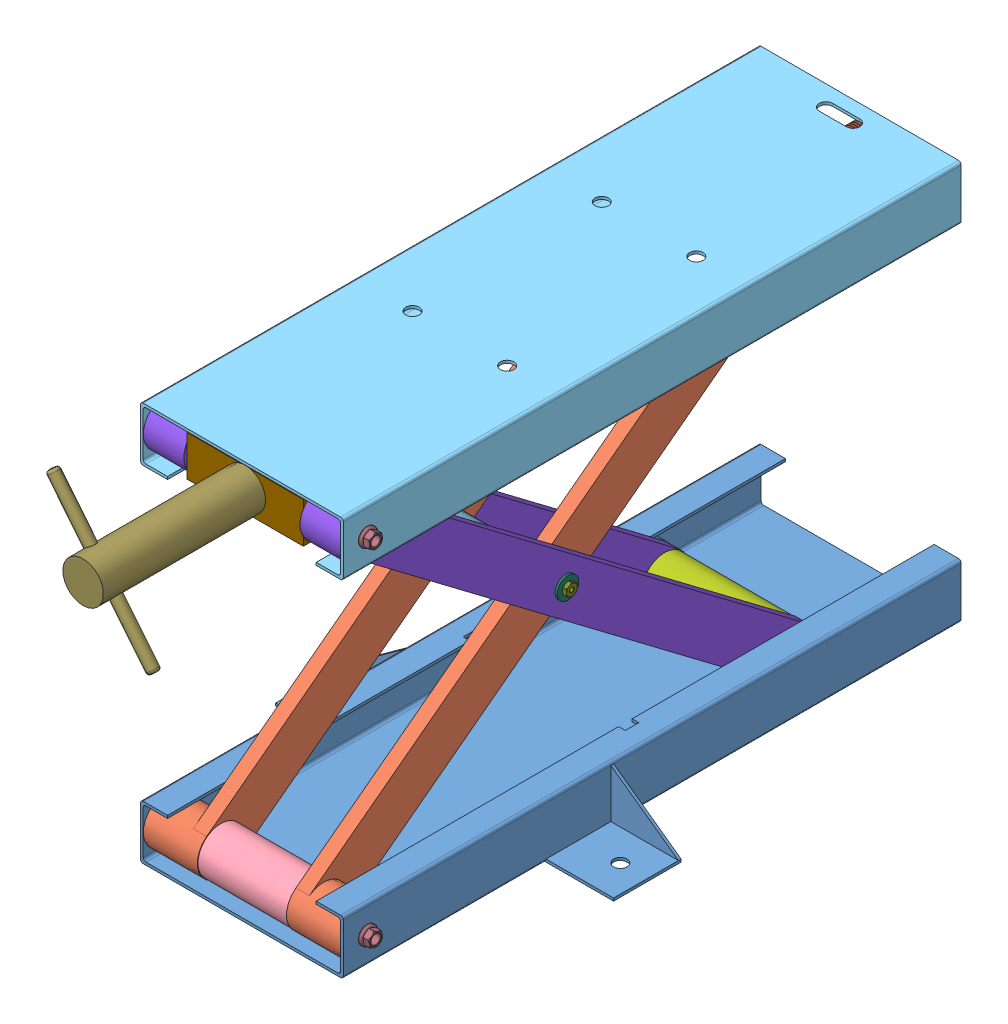
SolidWorks assembly Ensamblaje1, configuration Predeterminado. Lengths in mm.
Overall size (250 336.92 576.75).
25 component instances, 16 part files, 58 mates.
Components (placement in the parent):
- Base-1: Base [Predeterminado] at (-9.1737 1.9112 457.2) size (250 40 457.2)
- Pieza2-1: Pieza2 [Predeterminado] at (23.8263 129.7204 499.1586) x (0 0.602874 -0.797837) z (1 0 0) size (459 35 40)
- Pieza2-2: Pieza2 [Predeterminado] at (-42.1737 129.7204 499.1586) x (0 0.602874 -0.797837) z (-1 0 0) size (459 35 40)
- rueda-1: rueda [Predeterminado] at (-67.1737 257.5296 330.0173) x (0 -0.999437 -0.033543) z (1 0 0) size (35 35 30)
- rueda-2: rueda [Predeterminado] at (48.8263 257.5296 330.0173) x (0 0.027359 0.999626) z (-1 0 0) size (35 35 30)
- Pieza4-1: Pieza4 [Predeterminado] at (-9.1737 1.9112 668.3) x (0 0 -1) z (1 0 0) size (34 34 66)
- Base2-1: Base2 [Predeterminado] at (-9.1737 257.0296 457.2) x (-1 0 0) z (0 0 1) size (150 40 457.2)
- rueda2-1: rueda2 [Predeterminado] at (53.8263 1.4112 330.0173) x (0 0.027839 0.999612) z (-1 0 0) size (35 35 20)
- rueda2-2: rueda2 [Predeterminado] at (-72.1737 1.4112 330.0173) x (0 0.704882 0.709324) z (-1 0 0) size (35 35 20)
- Pieza5-1: Pieza5 [Predeterminado] at (-9.1737 1.4112 330.0173) x (0 -0.989655 -0.143469) z (-1 0 0) size (34 34 86)
- Pieza3-3: Pieza3 [Predeterminado] at (-52.1737 129.2204 499.1586) x (0 -0.602874 -0.797837) z (-1 0 0) size (459 35 30)
- Pieza3-4: Pieza3 [Predeterminado] at (33.8263 129.2204 499.1586) x (0 -0.602874 -0.797837) z (1 0 0) size (459 35 30)
- Pieza6-1: Pieza6 [Predeterminado] at (-9.1737 257.0296 668.3) size (86 30 30)
- Pieza7-1: Pieza7 [Predeterminado] at (-9.1737 257.5296 330.0173) size (66 30 30)
- rosca-1: rosca [Predeterminado] at (-9.1737 257.5296 683.3) x (-0.145567 0.989348 0) z (0 0 1) size (23.09 20.1 506.75)
- Pieza8-1: Pieza8 [Predeterminado] at (-9.1737 257.5296 683.3) x (0.776829 0.629712 0) z (0 0 1) size (30 120 120)
- hex nuts_21042_mil-4: hex nuts_21042_mil [NUT 21042 0.3125-24-N] at (72.5827 257.0296 668.3) x (0 0 -1) z (1 0 0) size (13.21 13.21 6.76)
- hex nuts_21042_mil-5: hex nuts_21042_mil [NUT 21042 0.3125-24-N] at (-90.9301 1.9112 668.3) x (0 -0.531517 0.847048) z (-1 0 0) size (13.21 13.21 6.76)
- hex nuts_21042_mil-6: hex nuts_21042_mil [NUT 21042 0.3125-24-N] at (72.5827 1.9112 668.3) x (0 -0.763369 -0.645962) z (1 0 0) size (13.21 13.21 6.76)
- hex nuts_21042_mil-7: hex nuts_21042_mil [NUT 21042 0.3125-24-N] at (-90.9301 257.0296 668.3) x (0 -0.851871 -0.523752) z (-1 0 0) size (13.21 13.21 6.76)
- Pieza9-1: Pieza9 [Predeterminado] at (-9.1737 129.2204 499.1586) x (0 0 1) z (-1 0 0) size (15 15 106)
- flat_mil-3: flat_mil [FLAT 0.281-0.625] at (43.8263 129.2204 499.1586) x (-1 0 0) z (0 0.924225 0.381849) size (1.65 15.88 15.88)
- flat_mil-4: flat_mil [FLAT 0.281-0.625] at (-62.1737 129.2204 499.1586) size (1.65 15.88 15.88)
- hex nuts_35650_mil-2: hex nuts_35650_mil [NUT 35650 0.138-40-N] at (48.3729 129.2204 499.1586) x (0 0 -1) z (1 0 0) size (8 9.24 2.9)
- hex nuts_35650_mil-3: hex nuts_35650_mil [NUT 35650 0.138-40-N] at (-66.7203 129.2204 499.1586) x (0 0 1) z (-1 0 0) size (8 9.24 2.9)
Mates (geometry in assembly coordinates):
- Concéntrica1: concentric anti-aligned: cylinder of Base-1 through (-84.1737 1.9112 668.3) axis (1 0 0) radius 5; cylinder of Pieza2-1 through (33.8263 1.9112 668.3) axis (-1 0 0) radius 5
- Coincidente1: coincident anti-aligned: plane of Base-1 through (63.8263 -16.0888 685.8) normal (-1 0 0); plane of Pieza2-1 through (63.8263 1.9112 668.3) normal (1 0 0)
- Coincidente2: coincident anti-aligned: plane of Base-1 through (-82.1737 -16.0888 685.8) normal (1 0 0); plane of Pieza2-2 through (-82.1737 1.9112 668.3) normal (-1 0 0)
- Concéntrica2: concentric aligned: cylinder of Base-1 through (-84.1737 1.9112 668.3) axis (1 0 0) radius 5; cylinder of Pieza2-2 through (-52.1737 1.9112 668.3) axis (1 0 0) radius 5
- Concéntrica3: concentric anti-aligned: cylinder of Pieza2-1 through (33.8263 257.5296 330.0173) axis (-1 0 0) radius 5; cylinder of rueda-2 through (33.8263 257.5296 330.0173) axis (1 0 0) radius 5
- Coincidente3: coincident anti-aligned: plane of Pieza2-1 through (33.8263 1.9112 668.3) normal (1 0 0); plane of rueda-2 through (33.8263 257.5296 330.0173) normal (-1 0 0)
- Concéntrica4: concentric anti-aligned: cylinder of Pieza2-2 through (-52.1737 257.5296 330.0173) axis (1 0 0) radius 5; cylinder of rueda-1 through (-52.1737 257.5296 330.0173) axis (-1 0 0) radius 5
- Coincidente4: coincident anti-aligned: plane of Pieza2-2 through (-52.1737 1.9112 668.3) normal (-1 0 0); plane of rueda-1 through (-52.1737 257.5296 330.0173) normal (1 0 0)
- Concéntrica5: concentric anti-aligned: cylinder of Pieza2-2 through (-52.1737 1.9112 668.3) axis (1 0 0) radius 5; cylinder of Pieza4-1 through (23.8263 1.9112 668.3) axis (-1 0 0) radius 5
- Coincidente5: coincident anti-aligned: plane of Pieza2-1 through (23.8263 1.9112 668.3) normal (-1 0 0); plane of Pieza4-1 through (23.8263 1.9112 668.3) normal (1 0 0)
- Tangente1: tangent anti-aligned: cylinder of rueda-2 through (33.8263 257.5296 330.0173) axis (1 0 0) radius 17.5; plane of Base2-1 through (63.8263 275.0296 685.8) normal (0 -1 0)
- Coincidente9: coincident aligned: plane of Base-1 through (65.8263 -18.0888 685.8) normal (1 0 0); plane of Base2-1 through (65.8263 277.0296 685.8) normal (1 0 0)
- Paralelo3: parallel aligned: plane of Base-1 through (-82.1737 -16.0888 685.8) normal (0 1 0); plane of Base2-1 through (65.8263 277.0296 685.8) normal (0 1 0)
- Tangente2: tangent anti-aligned: cylinder of rueda-1 through (-52.1737 257.5296 330.0173) axis (-1 0 0) radius 17.5; plane of Base2-1 through (63.8263 275.0296 685.8) normal (0 -1 0)
- Coincidente11: coincident aligned: plane of Base-1 through (-9.1737 1.9112 228.6) normal (0 0 -1); plane of Base2-1 through (-9.1737 257.0296 228.6) normal (0 0 -1)
- Distancia límite1: limit distance = 215.1184 mm anti-aligned: plane of Base-1 through (-84.1737 21.9112 685.8) normal (0 1 0); plane of Base2-1 through (-84.1737 237.0296 685.8) normal (0 -1 0)
- Coincidente14: coincident anti-aligned: plane of Base2-1 through (63.8263 275.0296 685.8) normal (-1 0 0); plane of rueda2-1 through (63.8263 1.4112 330.0173) normal (1 0 0)
- Coincidente16: coincident anti-aligned: plane of Base-1 through (-82.1737 -16.0888 685.8) normal (1 0 0); plane of rueda2-2 through (-82.1737 1.4112 330.0173) normal (-1 0 0)
- Tangente3: tangent anti-aligned: plane of Base-1 through (-82.1737 -16.0888 685.8) normal (0 1 0); cylinder of rueda2-2 through (-82.1737 1.4112 330.0173) axis (1 0 0) radius 17.5
- Tangente4: tangent anti-aligned: plane of Base-1 through (-82.1737 -16.0888 685.8) normal (0 1 0); cylinder of rueda2-1 through (43.8263 1.4112 330.0173) axis (1 0 0) radius 17.5
- Concéntrica13: concentric anti-aligned: cylinder of Base2-1 through (65.8263 257.0296 668.3) axis (-1 0 0) radius 5; cylinder of Pieza3-3 through (-62.1737 257.0296 668.3) axis (1 0 0) radius 5
- Coincidente19: coincident anti-aligned: plane of Base2-1 through (-82.1737 275.0296 685.8) normal (1 0 0); plane of Pieza3-3 through (-82.1737 257.0296 668.3) normal (-1 0 0)
- Concéntrica14: concentric aligned: cylinder of Pieza5-1 through (-52.1737 1.4112 330.0173) axis (1 0 0) radius 5; cylinder of Pieza3-3 through (-62.1737 1.4112 330.0173) axis (1 0 0) radius 5
- Coincidente20: coincident anti-aligned: plane of Pieza5-1 through (-52.1737 1.4112 330.0173) normal (-1 0 0); plane of Pieza3-3 through (-52.1737 257.0296 668.3) normal (1 0 0)
- Concéntrica16: concentric aligned: cylinder of rueda2-2 through (-82.1737 1.4112 330.0173) axis (1 0 0) radius 5; cylinder of Pieza3-3 through (-62.1737 1.4112 330.0173) axis (1 0 0) radius 5
- Coincidente21: coincident anti-aligned: plane of Base2-1 through (63.8263 275.0296 685.8) normal (-1 0 0); plane of Pieza3-4 through (63.8263 257.0296 668.3) normal (1 0 0)
- Concéntrica17: concentric aligned: cylinder of Base2-1 through (65.8263 257.0296 668.3) axis (-1 0 0) radius 5; cylinder of Pieza3-4 through (43.8263 257.0296 668.3) axis (-1 0 0) radius 5
- Concéntrica18: concentric anti-aligned: cylinder of rueda2-1 through (43.8263 1.4112 330.0173) axis (1 0 0) radius 5; cylinder of Pieza3-4 through (43.8263 1.4112 330.0173) axis (-1 0 0) radius 5
- Coincidente22: coincident anti-aligned: plane of Pieza3-4 through (33.8263 257.0296 668.3) normal (-1 0 0); plane of Pieza6-1 through (33.8263 242.0296 683.3) normal (1 0 0)
- Concéntrica19: concentric anti-aligned: cylinder of Base2-1 through (65.8263 257.0296 668.3) axis (-1 0 0) radius 5; cylinder of Pieza6-1 through (-52.1737 257.0296 668.3) axis (1 0 0) radius 5
- Paralelo4: parallel anti-aligned: plane of Base2-1 through (65.8263 277.0296 685.8) normal (0 1 0); plane of Pieza6-1 through (-52.1737 242.0296 683.3) normal (0 -1 0)
- Coincidente23: coincident anti-aligned: plane of Pieza2-1 through (23.8263 1.9112 668.3) normal (-1 0 0); plane of Pieza7-1 through (23.8263 242.5296 345.0173) normal (1 0 0)
- Concéntrica20: concentric anti-aligned: cylinder of Pieza2-1 through (33.8263 257.5296 330.0173) axis (-1 0 0) radius 5; cylinder of Pieza7-1 through (-42.1737 257.5296 330.0173) axis (1 0 0) radius 5
- Paralelo5: parallel aligned: plane of Base2-1 through (65.8263 277.0296 685.8) normal (0 1 0); plane of Pieza7-1 through (-42.1737 272.5296 345.0173) normal (0 1 0)
- Coincidente28: coincident anti-aligned: plane of Pieza6-1 through (-9.1737 257.0296 683.3) normal (0 0 1); plane of rosca-1 through (-9.1737 257.5296 683.3) normal (0 0 -1)
- Concéntrica26: concentric anti-aligned: cylinder of Pieza7-1 through (-9.1737 257.5296 345.0173) axis (0 0 -1) radius 7.5; cylinder of rosca-1 through (-9.1737 257.5296 228.3) axis (0 0 1) radius 7.5
- Tornillo5: screw = 50 mm aligned: circle of Pieza7-1; cylinder of rosca-1 through (-9.1737 257.5296 228.3) axis (0 0 1) radius 7.5
- Coincidente31: coincident anti-aligned: plane of Pieza6-1 through (-9.1737 257.0296 683.3) normal (0 0 1); plane of Pieza8-1 through (-9.1737 257.5296 683.3) normal (0 0 -1)
- Coincidente32: coincident anti-aligned: plane of rosca-1 through (-0.1806 264.7724 733.3) normal (0.360862 0.932619 0); plane of Pieza8-1 through (-10.9496 268.9393 733.3) normal (-0.360862 -0.932619 0)
- Coincidente33: coincident anti-aligned: plane of rosca-1 through (-10.9496 268.9393 733.3) normal (-0.627241 0.778825 0); plane of Pieza8-1 through (-19.9427 261.6965 733.3) normal (0.627241 -0.778825 0)
- Concéntrica28: concentric anti-aligned: cylinder of Base2-1 through (65.8263 257.0296 668.3) axis (-1 0 0) radius 5; cylinder of hex nuts_21042_mil-4 through (65.8263 257.0296 668.3) axis (1 0 0) radius 3.4544
- Coincidente35: coincident anti-aligned: plane of Base2-1 through (65.8263 277.0296 685.8) normal (1 0 0); plane of hex nuts_21042_mil-4 through (65.8263 257.0296 677.9012) normal (-1 0 0)
- Coincidente36: coincident anti-aligned: plane of Base-1 through (-84.1737 -18.0888 685.8) normal (-1 0 0); plane of hex nuts_21042_mil-5 through (-84.1737 7.0144 660.1673) normal (1 0 0)
- Concéntrica31: concentric anti-aligned: cylinder of Base-1 through (-84.1737 1.9112 668.3) axis (1 0 0) radius 5; cylinder of hex nuts_21042_mil-5 through (-84.1737 1.9112 668.3) axis (-1 0 0) radius 3.4544
- Coincidente37: coincident anti-aligned: plane of Base-1 through (65.8263 -18.0888 685.8) normal (1 0 0); plane of hex nuts_21042_mil-6 through (65.8263 9.2405 674.502) normal (-1 0 0)
- Concéntrica32: concentric aligned: cylinder of Base-1 through (-84.1737 1.9112 668.3) axis (1 0 0) radius 5; cylinder of hex nuts_21042_mil-6 through (65.8263 1.9112 668.3) axis (1 0 0) radius 3.4544
- Coincidente38: coincident aligned: plane of Base2-1 through (-84.1737 277.0296 685.8) normal (-1 0 0); circle of hex nuts_21042_mil-7
- Concéntrica33: concentric aligned: cylinder of Base2-1 through (65.8263 257.0296 668.3) axis (-1 0 0) radius 5; cylinder of hex nuts_21042_mil-7 through (-84.1737 257.0296 668.3) axis (-1 0 0) radius 3.4544
- Concéntrica34: concentric anti-aligned: cylinder of Pieza3-4 through (43.8263 129.2204 499.1586) axis (-1 0 0) radius 7.5; cylinder of Pieza9-1 through (-62.1737 129.2204 499.1586) axis (1 0 0) radius 7.5
- Coincidente39: coincident aligned: plane of Pieza3-4 through (43.8263 257.0296 668.3) normal (1 0 0); plane of Pieza9-1 through (43.8263 129.2204 499.1586) normal (1 0 0)
- Concéntrica38: concentric aligned: cylinder of Pieza9-1 through (-62.1737 129.2204 499.1586) axis (1 0 0) radius 7.5; cylinder of flat_mil-3 through (78.7513 129.2204 499.1586) axis (1 0 0) radius 3.5687
- Coincidente43: coincident anti-aligned: plane of Pieza9-1 through (43.8263 129.2204 499.1586) normal (1 0 0); plane of flat_mil-3 through (43.8263 127.8577 502.4569) normal (-1 0 0)
- Concéntrica39: concentric anti-aligned: cylinder of Pieza3-3 through (-62.1737 129.2204 499.1586) axis (1 0 0) radius 7.5; cylinder of flat_mil-4 through (-97.0987 129.2204 499.1586) axis (-1 0 0) radius 3.5687
- Coincidente44: coincident anti-aligned: plane of Pieza3-3 through (-62.1737 257.0296 668.3) normal (-1 0 0); plane of flat_mil-4 through (-62.1737 132.7891 499.1586) normal (1 0 0)
- Concéntrica40: concentric aligned: cylinder of flat_mil-3 through (78.7513 129.2204 499.1586) axis (1 0 0) radius 3.5687; cylinder of hex nuts_35650_mil-2 through (23.3354 129.2204 499.1586) axis (1 0 0) radius 1.7526
- Coincidente46: coincident anti-aligned: plane of flat_mil-3 through (45.4773 126.1895 506.4947) normal (1 0 0); plane of hex nuts_35650_mil-2 through (45.4773 133.8398 499.1586) normal (-1 0 0)
- Concéntrica41: concentric aligned: cylinder of flat_mil-4 through (-97.0987 129.2204 499.1586) axis (-1 0 0) radius 3.5687; cylinder of hex nuts_35650_mil-3 through (-41.6828 129.2204 499.1586) axis (-1 0 0) radius 1.7526
- Coincidente47: coincident anti-aligned: plane of flat_mil-4 through (-63.8247 137.1579 499.1586) normal (-1 0 0); plane of hex nuts_35650_mil-3 through (-63.8247 133.8398 499.1586) normal (1 0 0)
